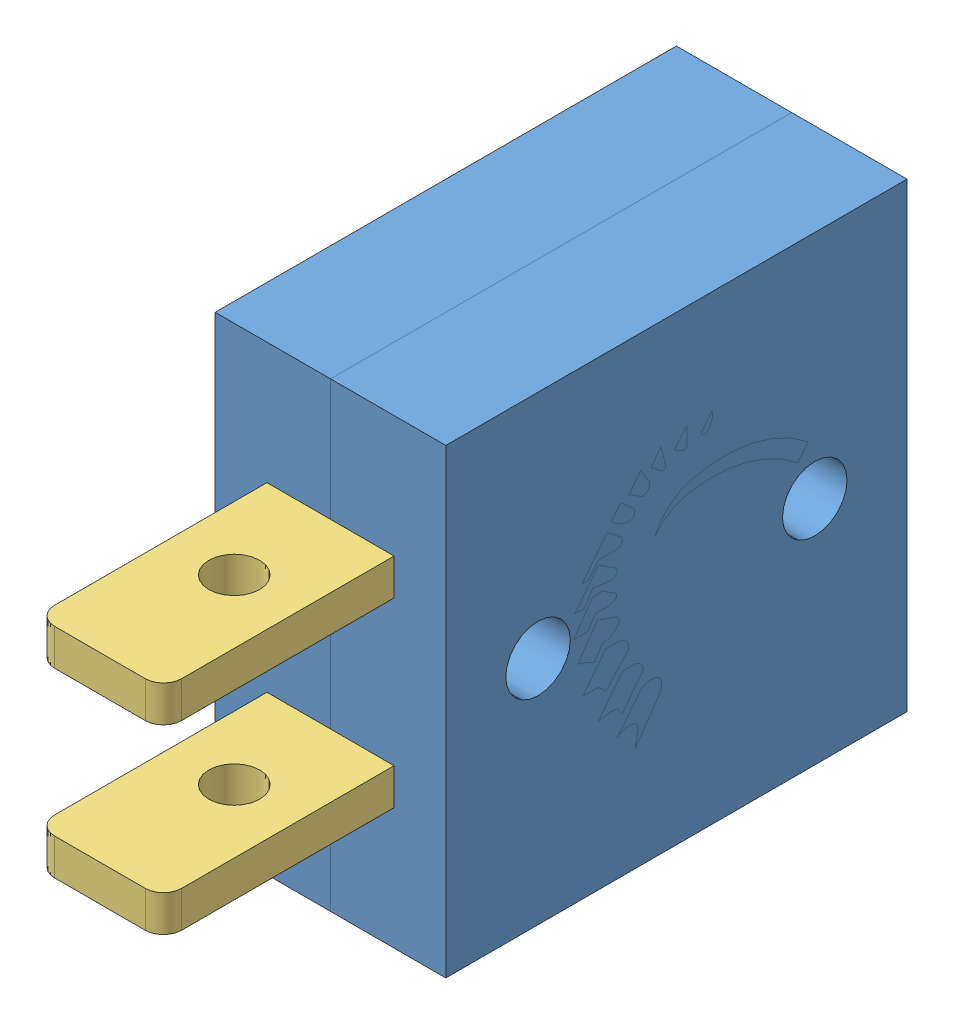
SolidWorks assembly Fingertech Mini Power Switch, configuration Default. Lengths in mm.
Overall size (6.35 12.88 19.05).
5 component instances, 3 part files, 11 mates.
Components (placement in the parent):
- PART A-1: PART A [Default] at origin size (3.17 12.7 12.7)
- PART A-2: PART A [Default] x (-1 0 0) z (0 0 -1) size (3.17 12.7 12.7)
- socket head cap screw_ai-1: socket head cap screw_ai [HX-SHCS 0.086-56x0.375x0.375-S] at (0 -6.5344 0) x (0 1 0) z (0 0 1) size (11.71 3.56 3.56)
- TERMINAL-1: TERMINAL [Default] at (0 2 3.7) x (0 0 -1) z (0 1 0) size (18 3.5 1)
- TERMINAL-2: TERMINAL [Default] at (0 -3 3.7) x (0 0 -1) z (0 1 0) size (18 3.5 1)
Mates (geometry in assembly coordinates):
- Coincident1: coincident anti-aligned: plane of PART A-2 through (0 0 0) normal (1 0 0); plane of PART A-1 through (0 0 0) normal (-1 0 0)
- Coincident2: coincident aligned: plane of PART A-1 through (3.175 -6.35 6.35) normal (0 -1 0); plane of PART A-2 through (-3.175 -6.35 -6.35) normal (0 -1 0)
- Coincident3: coincident aligned: plane of PART A-1 through (3.175 6.35 -6.35) normal (0 0 -1); plane of PART A-2 through (-3.175 6.35 -6.35) normal (0 0 -1)
- Concentric1: concentric aligned: cylinder of PART A-1 through (0 -4.35 0) axis (0 -1 0) radius 2; cylinder of socket head cap screw_ai-1 through (0 -38.2844 0) axis (0 -1 0) radius 1.778
- Coincident4: coincident anti-aligned: plane of PART A-1 through (0 -4.35 0) normal (0 -1 0); plane of socket head cap screw_ai-1 through (-1.778 -4.35 0) normal (0 1 0)
- Coincident5: coincident anti-aligned: plane of PART A-1 through (1.75 3 -6.35) normal (-1 0 0); plane of TERMINAL-1 through (1.75 3 12.7) normal (1 0 0)
- Coincident7: coincident anti-aligned: plane of PART A-1 through (0 2 -6.35) normal (0 1 0); plane of TERMINAL-1 through (0 2 3.7) normal (0 -1 0)
- Distance1: distance = 6.35 mm: line of TERMINAL-1 through (-1.25 2 12.7) axis (1 0 0); plane of PART A-1 through (3.175 6.35 6.35) normal (0 0 1)
- Coincident9: coincident anti-aligned: plane of PART A-1 through (1.75 -3 -6.35) normal (-1 0 0); plane of TERMINAL-2 through (1.75 -2 12.7) normal (1 0 0)
- Coincident10: coincident anti-aligned: plane of PART A-1 through (0 -3 -6.35) normal (0 1 0); plane of TERMINAL-2 through (0 -3 3.7) normal (0 -1 0)
- Coincident11: coincident aligned: plane of TERMINAL-1 through (-1.75 3 12.7) normal (0 0 1); plane of TERMINAL-2 through (-1.75 -2 12.7) normal (0 0 1)
